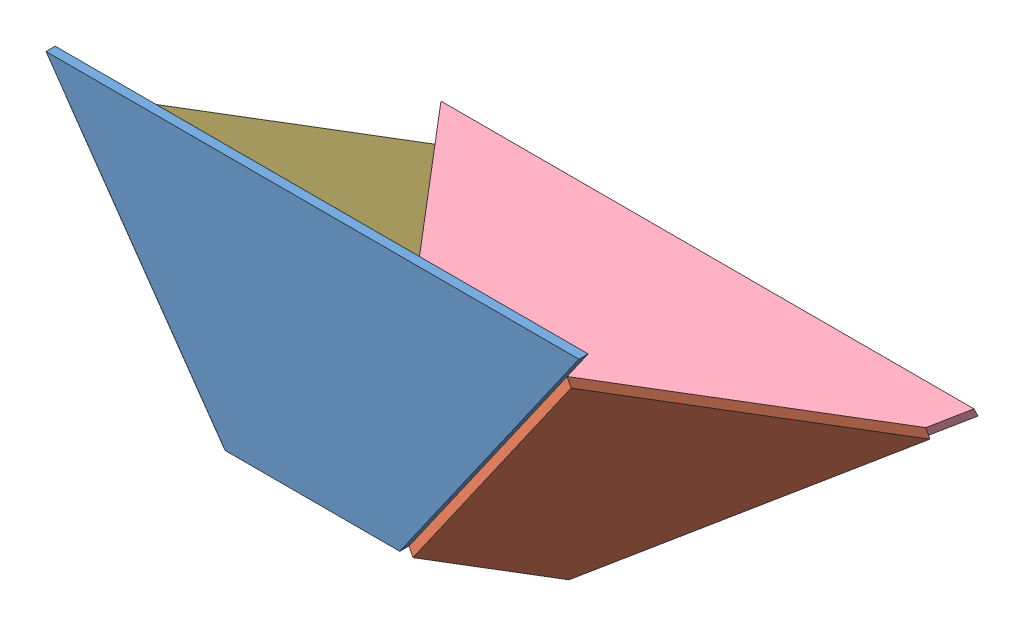
SolidWorks assembly funnel, configuration Default. Lengths in mm.
Overall size (580 458.49 537.88).
4 component instances, 4 part files, 8 mates.
Components (placement in the parent):
- b-1: b [Default] at (271.4915 234.4213 462.4973) size (580 278.52 10)
- r-1: r [Default] at (366.4915 181.5232 377.6339) x (0 -0.528981 -0.848634) z (0.771374 -0.540056 0.336634) size (460 270.37 10)
- l-1: l [Default] at (176.4915 181.5232 377.6339) x (0 0.528981 0.848634) z (-0.771374 -0.540056 0.336634) size (460 270.37 10)
- f-1: f [Default] at (271.4915 119.6469 288.367) x (1 0 0) z (0 0.897822 0.440358) size (580 278.52 10)
Mates (geometry in assembly coordinates):
- Coincident27: coincident: point of b-1; point of r-1
- Coincident28: coincident: point of b-1; point of l-1
- Coincident29: coincident: point of r-1; point of f-1
- Coincident30: coincident: point of l-1; point of f-1
- Coincident31: coincident anti-aligned: line of b-1 through (366.4915 234.4213 462.4973) axis (0.573529 0.819185 0); line of r-1 through (538.5503 480.1768 462.4973) axis (-0.573529 -0.819185 0)
- Coincident32: coincident anti-aligned: line of b-1 through (-18.5085 512.9442 462.4973) axis (0.573529 -0.819185 0); line of l-1 through (176.4915 234.4213 462.4973) axis (-0.573529 0.819185 0)
- Coincident33: coincident aligned: line of l-1 through (4.4327 236.8455 72.1258) axis (0.573529 -0.360735 0.735482); line of f-1 through (-18.5085 251.2749 42.7065) axis (0.573529 -0.360735 0.735482)
- Coincident34: coincident aligned: line of r-1 through (366.4915 128.6251 292.7705) axis (0.573529 0.360735 -0.735482); line of f-1 through (366.4915 128.6251 292.7705) axis (0.573529 0.360735 -0.735482)
